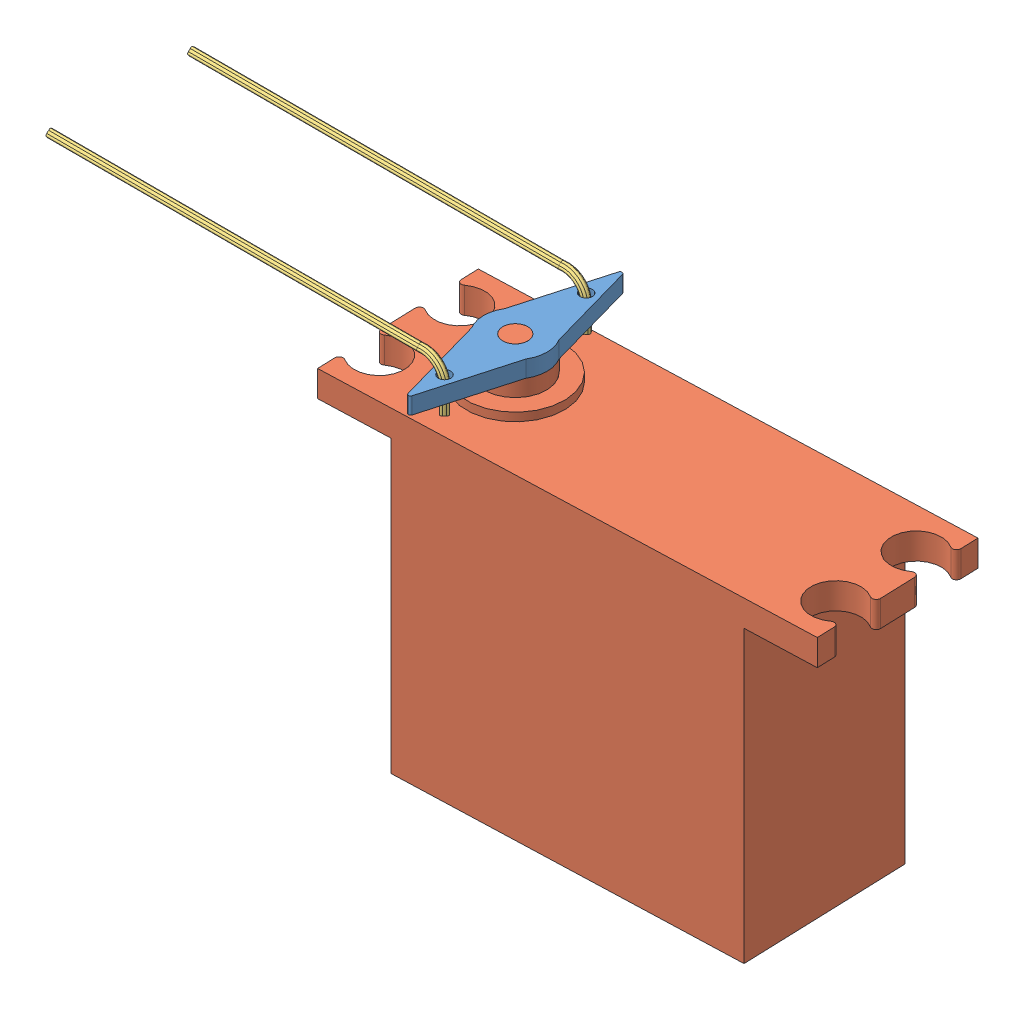
SolidWorks assembly Assem2, configuration Default. Lengths in mm.
Overall size (98.52 44.98 25.64).
4 component instances, 3 part files, 8 mates.
Components (placement in the parent):
- ServoHead-1: ServoHead [Default] at (5.531 14.0449 21.3581) size (7.62 2 25.64)
- Servo-1: Servo [Default] at (21.2456 -7.9551 30.8167) x (0.999394 0 -0.034816) z (0.034816 0 0.999394) size (58 43 20)
- string2-1: string2 [Default] at (5.531 12.0449 29.8581) size (47.84 5.98 1.03)
- string2-2: string2 [Default] at (5.531 12.0449 12.8581) size (47.84 5.98 1.03)
Mates (geometry in assembly coordinates):
- Concentric1: concentric aligned: cylinder of ServoHead-1 through (5.531 16.0449 21.3581) axis (0 -1 0) radius 1.5; cylinder of Servo-1 through (5.531 16.0449 21.3581) axis (0 -1 0) radius 1.5
- Coincident4: coincident anti-aligned: plane of ServoHead-1 through (5.531 14.0449 21.3581) normal (0 -1 0); plane of Servo-1 through (5.531 14.0449 21.3581) normal (0 1 0)
- Concentric2: concentric anti-aligned: cylinder of ServoHead-1 through (5.531 11.9235 29.8581) axis (0 1 0) radius 0.75; cylinder of string2-1 through (5.531 15.0449 29.8581) axis (0 -1 0) radius 0.4797
- Concentric3: concentric anti-aligned: cylinder of ServoHead-1 through (5.531 11.9235 12.8581) axis (0 1 0) radius 0.75; cylinder of string2-2 through (5.531 15.0449 12.8581) axis (0 -1 0) radius 0.4797
- Parallel5: parallel aligned: plane of string2-2 through (5.531 12.0449 12.8581) normal (0 0 1); plane of assembly
- Parallel6: parallel aligned: plane of string2-1 through (5.531 12.0449 29.8581) normal (0 0 1); plane of assembly
- Coincident11: coincident anti-aligned: plane of Servo-1 through (5.531 12.0449 21.3581) normal (0 1 0); plane of string2-1 through (5.531 12.0449 29.8581) normal (0 -1 0)
- Coincident12: coincident anti-aligned: plane of Servo-1 through (5.531 12.0449 21.3581) normal (0 1 0); plane of string2-2 through (5.531 12.0449 12.8581) normal (0 -1 0)
